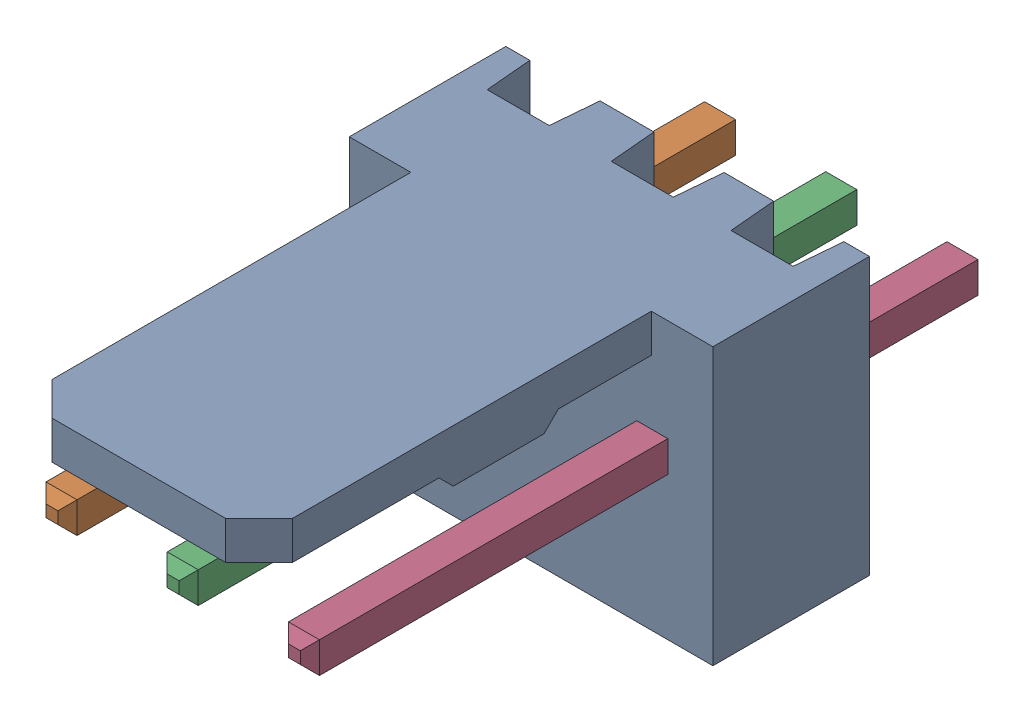
SolidWorks assembly Molex PCB 3 pin v2 v6_5, configuration Default. Lengths in mm.
Overall size (7.62 5.79 14.92).
4 component instances, 2 part files, 0 mates.
Components (placement in the parent):
- BASE9710016 (1)-1: BASE9710016 (1) [Default] at (2.54 2.895 -8.22) size (7.62 5.79 11.5)
- PINO9710016 (1)-1: PINO9710016 (1) [Default] at (1.27 3.325 -0.72) size (0.65 0.65 14.2)
- PINO9710016 (1)-2: PINO9710016 (1) [Default] at (3.81 3.325 -0.72) size (0.65 0.65 14.2)
- PINO9710016 (1)-3: PINO9710016 (1) [Default] at (6.35 3.325 -0.72) size (0.65 0.65 14.2)
